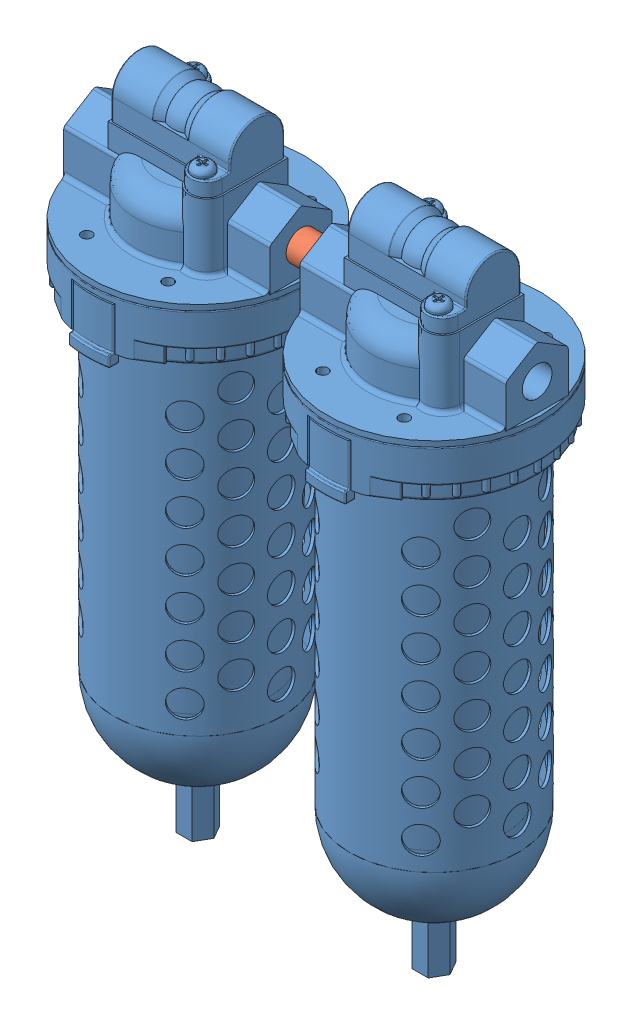
SolidWorks assembly ReadingTech_3P-060-P02-DCi, configuration Default. Lengths in mm.
Overall size (206.63 296.8 99.95).
3 component instances, 2 part files, 3 mates.
Components (placement in the parent):
- ReadingTech_3P060P02Fi-1: ReadingTech_3P060P02Fi [Default] at (-7.2311 -90.0577 -9.4447) size (98.17 296.8 99.95)
- ReadingTech_3P060P02Fi-2: ReadingTech_3P060P02Fi [Default] at (101.2269 -90.0577 -9.4447) size (98.17 296.8 99.95)
- ReadingTech- 60cfm_connector_.25in-1: ReadingTech- 60cfm_connector_.25in [Default] at (53.8559 125.8423 -9.4447) x (0 1 0) z (0 0 1) size (13.72 13.72 13.72)
Mates (geometry in assembly coordinates):
- Coincident1: coincident anti-aligned: circle of ReadingTech_3P060P02Fi-1; circle of ReadingTech- 60cfm_connector_.25in-1
- Coincident2: coincident aligned: circle of ReadingTech_3P060P02Fi-2; circle of ReadingTech- 60cfm_connector_.25in-1
- Coincident3: coincident aligned: plane of ReadingTech_3P060P02Fi-1 through (40.1399 113.1423 4.8428) normal (0 0 1); plane of ReadingTech_3P060P02Fi-2 through (148.5979 113.1423 4.8428) normal (0 0 1)
